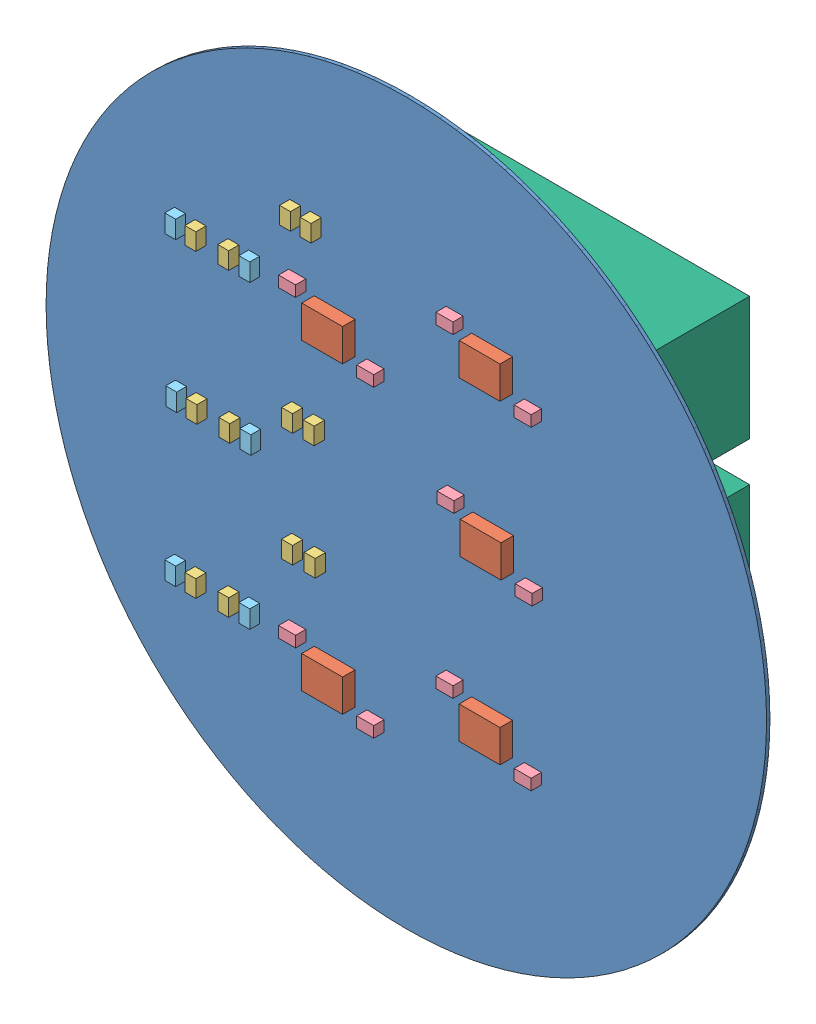
SolidWorks assembly sonar_DAQ, configuration Default. Lengths in mm.
Overall size (88.92 88.92 18.3).
124 component instances, 7 part files, 0 mates.
Components (placement in the parent):
- Board-1: Board [Default] at (0 0 -0.4039) size (88.92 88.92 0.42)
- OP5-1: OP5 [Default] at origin size (5.04 3.99 1.55)
  - 407985952-1: 407985952 [Default] at (35.814 22.733 0.2157) size (5.04 3.99 1.55)
    - Extruded-1: Extruded [Default] at origin size (5.04 3.99 1.55)
- OP4-1: OP4 [Default] at origin size (5.04 3.99 1.55)
  - 407985952-1: 407985952 [Default] at (35.814 60.198 0.2157) size (5.04 3.99 1.55)
    - Extruded-1: Extruded [Default] at origin size (5.04 3.99 1.55)
- OP3-1: OP3 [Default] at origin size (5.04 3.99 1.55)
  - 407985952-1: 407985952 [Default] at (55.245 27.051 0.2157) size (5.04 3.99 1.55)
    - Extruded-1: Extruded [Default] at origin size (5.04 3.99 1.55)
- OP2-1: OP2 [Default] at origin size (5.04 3.99 1.55)
  - 407985952-1: 407985952 [Default] at (55.372 46.863 0.2157) size (5.04 3.99 1.55)
    - Extruded-1: Extruded [Default] at origin size (5.04 3.99 1.55)
- OP1-1: OP1 [Default] at origin size (5.04 3.99 1.55)
  - 407985952-1: 407985952 [Default] at (55.245 65.913 0.2157) size (5.04 3.99 1.55)
    - Extruded-1: Extruded [Default] at origin size (5.04 3.99 1.55)
- CL3-1: CL3 [Default] at origin size (1.35 2.1 1.26)
  - 407985696-1: 407985696 [Default] at (30.988 34.163 0.0127) size (1.35 2.1 1.26)
    - Extruded_1-1: Extruded_1 [Default] at origin size (1.35 2.1 1.26)
- CL2-1: CL2 [Default] at origin size (1.35 2.1 1.26)
  - 407985696-1: 407985696 [Default] at (30.988 48.2476 0.0127) size (1.35 2.1 1.26)
    - Extruded_1-1: Extruded_1 [Default] at origin size (1.35 2.1 1.26)
- CL1-1: CL1 [Default] at origin size (1.35 2.1 1.26)
  - 407985696-1: 407985696 [Default] at (30.734 69.723 0.0127) size (1.35 2.1 1.26)
    - Extruded_1-1: Extruded_1 [Default] at origin size (1.35 2.1 1.26)
- C53-1: C53 [Default] at origin size (2.1 1.35 1.26)
  - 407985824-1: 407985824 [Default] at (40.64 20.2946 0.0127) size (2.1 1.35 1.26)
    - Extruded_2-1: Extruded_2 [Default] at origin size (2.1 1.35 1.26)
- C52-1: C52 [Default] at origin size (2.1 1.35 1.26)
  - 407985824-1: 407985824 [Default] at (30.988 25.1206 0.0127) size (2.1 1.35 1.26)
    - Extruded_2-1: Extruded_2 [Default] at origin size (2.1 1.35 1.26)
- C43-1: C43 [Default] at origin size (2.1 1.35 1.26)
  - 407985824-1: 407985824 [Default] at (40.64 57.8104 0.0127) size (2.1 1.35 1.26)
    - Extruded_2-1: Extruded_2 [Default] at origin size (2.1 1.35 1.26)
- C42-1: C42 [Default] at origin size (2.1 1.35 1.26)
  - 407985824-1: 407985824 [Default] at (30.988 62.5856 0.0127) size (2.1 1.35 1.26)
    - Extruded_2-1: Extruded_2 [Default] at origin size (2.1 1.35 1.26)
- C33-1: C33 [Default] at origin size (2.1 1.35 1.26)
  - 407985824-1: 407985824 [Default] at (60.071 24.384 0.0127) size (2.1 1.35 1.26)
    - Extruded_2-1: Extruded_2 [Default] at origin size (2.1 1.35 1.26)
- C32-1: C32 [Default] at origin size (2.1 1.35 1.26)
  - 407985824-1: 407985824 [Default] at (50.419 29.4386 0.0127) size (2.1 1.35 1.26)
    - Extruded_2-1: Extruded_2 [Default] at origin size (2.1 1.35 1.26)
- C31-1: C31 [Default] at origin size (1.35 2.1 1.26)
  - 407985696-1: 407985696 [Default] at (33.782 34.163 0.0127) size (1.35 2.1 1.26)
    - Extruded_1-1: Extruded_1 [Default] at origin size (1.35 2.1 1.26)
- C23-1: C23 [Default] at origin size (2.1 1.35 1.26)
  - 407985824-1: 407985824 [Default] at (60.198 44.196 0.0127) size (2.1 1.35 1.26)
    - Extruded_2-1: Extruded_2 [Default] at origin size (2.1 1.35 1.26)
- C22-1: C22 [Default] at origin size (2.1 1.35 1.26)
  - 407985824-1: 407985824 [Default] at (50.546 49.276 0.0127) size (2.1 1.35 1.26)
    - Extruded_2-1: Extruded_2 [Default] at origin size (2.1 1.35 1.26)
- C21-1: C21 [Default] at origin size (1.35 2.1 1.26)
  - 407985696-1: 407985696 [Default] at (33.655 48.2476 0.0127) size (1.35 2.1 1.26)
    - Extruded_1-1: Extruded_1 [Default] at origin size (1.35 2.1 1.26)
- C12.-1: C12. [Default] at origin size (1.35 2.2 1.2)
  - 407985568-1: 407985568 [Default] at (16.51 24.638 0.0127) size (1.35 2.2 1.2)
    - Extruded_3-1: Extruded_3 [Default] at origin size (1.35 2.2 1.2)
- C11.-1: C11. [Default] at origin size (1.35 2.1 1.26)
  - 407985696-1: 407985696 [Default] at (19.05 24.638 0.0127) size (1.35 2.1 1.26)
    - Extruded_1-1: Extruded_1 [Default] at origin size (1.35 2.1 1.26)
- C10-1: C10 [Default] at origin size (1.35 2.1 1.26)
  - 407985696-1: 407985696 [Default] at (23.114 24.638 0.0127) size (1.35 2.1 1.26)
    - Extruded_1-1: Extruded_1 [Default] at origin size (1.35 2.1 1.26)
- C9-1: C9 [Default] at origin size (1.35 2.2 1.2)
  - 407985568-1: 407985568 [Default] at (25.654 24.638 0.0127) size (1.35 2.2 1.2)
    - Extruded_3-1: Extruded_3 [Default] at origin size (1.35 2.2 1.2)
- C8-1: C8 [Default] at origin size (1.35 2.2 1.2)
  - 407985568-1: 407985568 [Default] at (16.637 43.307 0.0127) size (1.35 2.2 1.2)
    - Extruded_3-1: Extruded_3 [Default] at origin size (1.35 2.2 1.2)
- C7-1: C7 [Default] at origin size (1.35 2.1 1.26)
  - 407985696-1: 407985696 [Default] at (19.177 43.307 0.0127) size (1.35 2.1 1.26)
    - Extruded_1-1: Extruded_1 [Default] at origin size (1.35 2.1 1.26)
- C6-1: C6 [Default] at origin size (1.35 2.1 1.26)
  - 407985696-1: 407985696 [Default] at (23.241 43.307 0.0127) size (1.35 2.1 1.26)
    - Extruded_1-1: Extruded_1 [Default] at origin size (1.35 2.1 1.26)
- C5-1: C5 [Default] at origin size (1.35 2.2 1.2)
  - 407985568-1: 407985568 [Default] at (25.781 43.307 0.0127) size (1.35 2.2 1.2)
    - Extruded_3-1: Extruded_3 [Default] at origin size (1.35 2.2 1.2)
- C13-1: C13 [Default] at origin size (2.1 1.35 1.26)
  - 407985824-1: 407985824 [Default] at (60.071 63.246 0.0127) size (2.1 1.35 1.26)
    - Extruded_2-1: Extruded_2 [Default] at origin size (2.1 1.35 1.26)
- C4-1: C4 [Default] at origin size (1.35 2.2 1.2)
  - 407985568-1: 407985568 [Default] at (16.51 61.722 0.0127) size (1.35 2.2 1.2)
    - Extruded_3-1: Extruded_3 [Default] at origin size (1.35 2.2 1.2)
- C3-1: C3 [Default] at origin size (1.35 2.1 1.26)
  - 407985696-1: 407985696 [Default] at (19.05 61.722 0.0127) size (1.35 2.1 1.26)
    - Extruded_1-1: Extruded_1 [Default] at origin size (1.35 2.1 1.26)
- C12-1: C12 [Default] at origin size (2.1 1.35 1.26)
  - 407985824-1: 407985824 [Default] at (50.419 68.326 0.0127) size (2.1 1.35 1.26)
    - Extruded_2-1: Extruded_2 [Default] at origin size (2.1 1.35 1.26)
- C2-1: C2 [Default] at origin size (1.35 2.1 1.26)
  - 407985696-1: 407985696 [Default] at (23.114 61.722 0.0127) size (1.35 2.1 1.26)
    - Extruded_1-1: Extruded_1 [Default] at origin size (1.35 2.1 1.26)
- C1-1: C1 [Default] at origin size (1.35 2.2 1.2)
  - 407985568-1: 407985568 [Default] at (25.654 61.722 0.0127) size (1.35 2.2 1.2)
    - Extruded_3-1: Extruded_3 [Default] at origin size (1.35 2.2 1.2)
- C11-1: C11 [Default] at origin size (1.35 2.1 1.26)
  - 407985696-1: 407985696 [Default] at (33.274 69.723 0.0127) size (1.35 2.1 1.26)
    - Extruded_1-1: Extruded_1 [Default] at origin size (1.35 2.1 1.26)
- CP3-1: CP3 [Default] at origin size (1.35 2.2 1.2)
  - 407985568-1: 407985568 [Default] at (80.01 61.3918 -1.6039) size (1.35 2.2 1.2)
    - Extruded_3-1: Extruded_3 [Default] at origin size (1.35 2.2 1.2)
- CP2-1: CP2 [Default] at origin size (1.35 2.2 1.2)
  - 407985568-1: 407985568 [Default] at (77.5208 61.3918 -1.6039) size (1.35 2.2 1.2)
    - Extruded_3-1: Extruded_3 [Default] at origin size (1.35 2.2 1.2)
- CP1-1: CP1 [Default] at origin size (1.35 2.2 1.2)
  - 407985568-1: 407985568 [Default] at (74.4982 65.532 -1.6039) size (1.35 2.2 1.2)
    - Extruded_3-1: Extruded_3 [Default] at origin size (1.35 2.2 1.2)
- H3-1: H3 [Default] at origin size (46.99 15.24 16.13)
  - 407985440-1: 407985440 [Default] at (47.1043 24.3586 -16.5329) size (46.35 15.24 16.13)
    - Extruded_4-1: Extruded_4 [Default] at origin size (46.35 15.24 16.13)
  - 407985312-1: 407985312 [Default] at (23.6093 24.3586 -16.2789) size (0.64 14.61 15.88)
    - Extruded_5-1: Extruded_5 [Default] at origin size (0.64 14.61 15.88)
- H2-1: H2 [Default] at origin size (46.99 15.24 16.13)
  - 407985440-1: 407985440 [Default] at (47.1043 44.5008 -16.5329) size (46.35 15.24 16.13)
    - Extruded_4-1: Extruded_4 [Default] at origin size (46.35 15.24 16.13)
  - 407985312-1: 407985312 [Default] at (23.6093 44.5008 -16.2789) size (0.64 14.61 15.88)
    - Extruded_5-1: Extruded_5 [Default] at origin size (0.64 14.61 15.88)
- H1-1: H1 [Default] at origin size (46.99 15.24 16.13)
  - 407985440-1: 407985440 [Default] at (47.1043 64.643 -16.5329) size (46.35 15.24 16.13)
    - Extruded_4-1: Extruded_4 [Default] at origin size (46.35 15.24 16.13)
  - 407985312-1: 407985312 [Default] at (23.6093 64.643 -16.2789) size (0.64 14.61 15.88)
    - Extruded_5-1: Extruded_5 [Default] at origin size (0.64 14.61 15.88)
